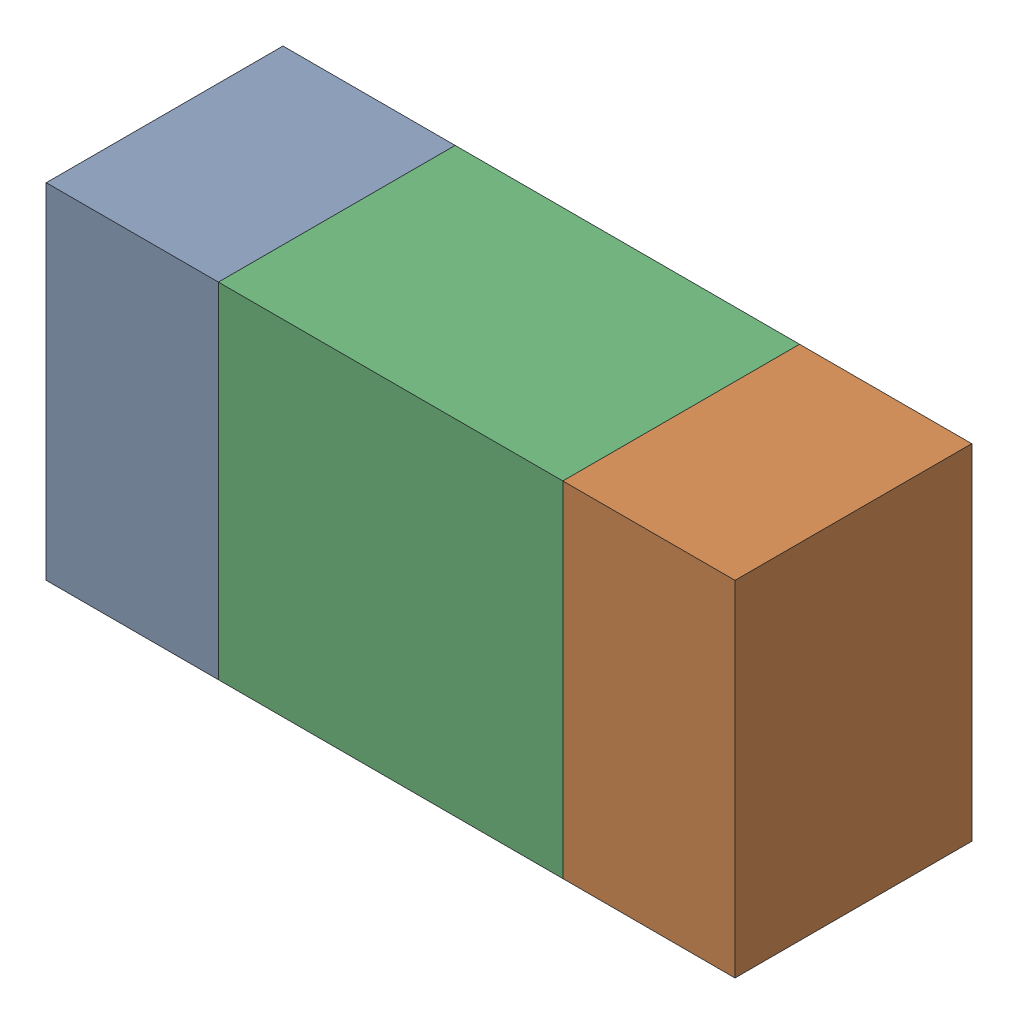
SolidWorks assembly R51, configuration ﾃﾞﾌｫﾙﾄ. Lengths in mm.
Overall size (1.6 0.8 0.55).
6 component instances, 2 part files, 0 mates.
Components (placement in the parent):
- 689261512-1: 689261512 [ﾃﾞﾌｫﾙﾄ] at (56.8676 49.2126 0) size (0.4 0.8 0.55)
  - Extruded_32-1: Extruded_32 [ﾃﾞﾌｫﾙﾄ] at origin size (0.4 0.8 0.55)
- 689261512-2: 689261512 [ﾃﾞﾌｫﾙﾄ] at (58.0676 49.2126 0) size (0.4 0.8 0.55)
  - Extruded_32-1: Extruded_32 [ﾃﾞﾌｫﾙﾄ] at origin size (0.4 0.8 0.55)
- 689261648-1: 689261648 [ﾃﾞﾌｫﾙﾄ] at (57.4675 49.2126 0) size (0.8 0.8 0.55)
  - Extruded_33-1: Extruded_33 [ﾃﾞﾌｫﾙﾄ] at origin size (0.8 0.8 0.55)
